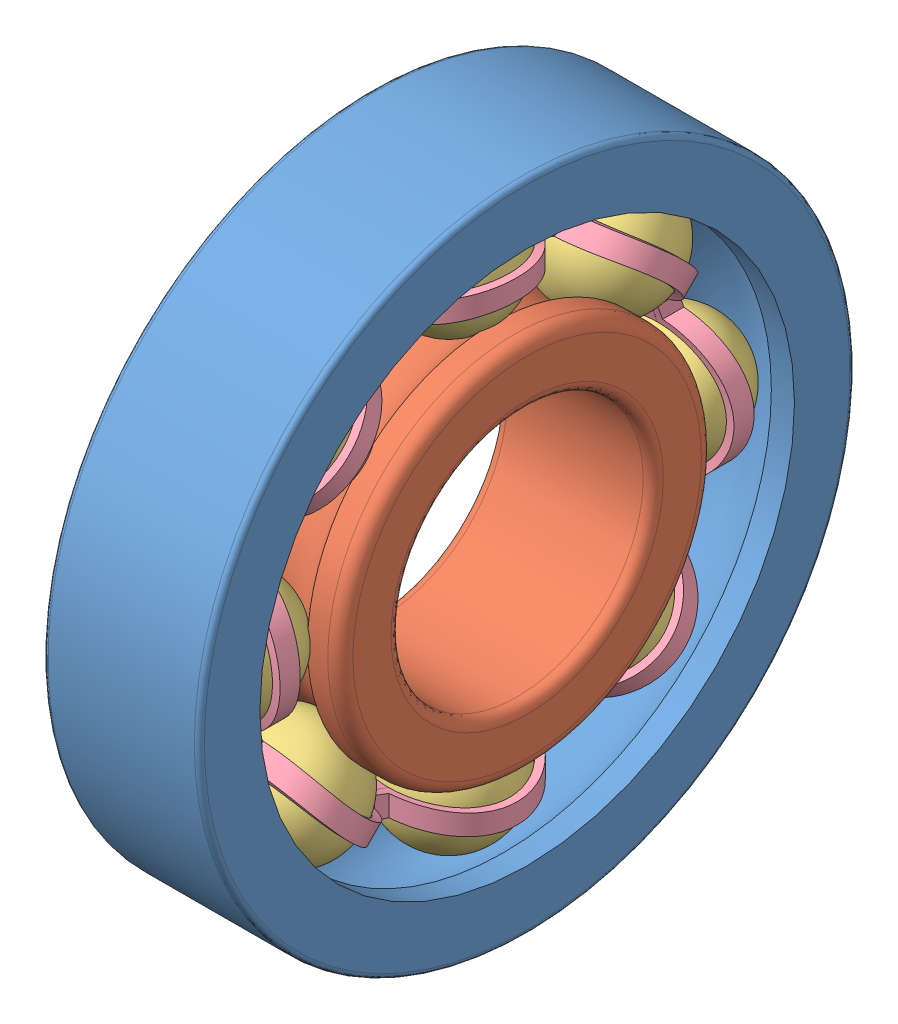
SolidWorks assembly Assem2, configuration Default. Lengths in mm.
Overall size (31 132.94 132.94).
22 component instances, 5 part files, 9 mates.
Components (placement in the parent):
- ball bearing 1-1: ball bearing 1 [Default] at origin size (31 132.94 132.94)
  - ball bearing-1: ball bearing [Default] at origin size (31 130 130)
    - Outer ring 1-1: Outer ring 1 [Default] at origin size (31 130 130)
    - Inner ring 1-1: Inner ring 1 [Default] at origin size (31 74.08 74.08)
    - ss ball-2: ss ball [Default] at (0 44.3297 0) size (24 24 24)
    - ss ball-3: ss ball [Default] at (0 31.3458 -31.3458) x (1 0 0) z (0 0.707107 0.707107) size (24 24 24)
    - ss ball-4: ss ball [Default] at (0 0 -44.3297) x (1 0 0) z (0 1 0) size (24 24 24)
    - ss ball-5: ss ball [Default] at (0 -31.3458 -31.3458) x (1 0 0) z (0 0.707107 -0.707107) size (24 24 24)
    - ss ball-6: ss ball [Default] at (0 -44.3297 0) x (1 0 0) z (0 0 -1) size (24 24 24)
    - ss ball-7: ss ball [Default] at (0 -31.3458 31.3458) x (1 0 0) z (0 -0.707107 -0.707107) size (24 24 24)
    - ss ball-8: ss ball [Default] at (0 0 44.3297) x (1 0 0) z (0 -1 0) size (24 24 24)
    - ss ball-9: ss ball [Default] at (0 31.3458 31.3458) x (1 0 0) z (0 -0.707107 0.707107) size (24 24 24)
  - cage-1: cage [Default] at (14 0 0) x (0 0 1) z (-1 0 0) size (94 94 14.93)
  - cage-2: cage [Default] at (-14 0 0) x (0 -0.707107 -0.707107) z (1 0 0) size (94 94 14.93)
- nut ball-1: nut ball [Default] at (0.1 -41.5746 17.2208) x (0 0 -1) z (1 0 0) size (2.3 2.3 1.4)
- nut ball-2: nut ball [Default] at (0.1 -17.2208 -41.5746) x (0 0 -1) z (1 0 0) size (2.3 2.3 1.4)
- nut ball-3: nut ball [Default] at (0.1 -41.5746 -17.2208) x (0 0 -1) z (1 0 0) size (2.3 2.3 1.4)
- nut ball-4: nut ball [Default] at (0.1 17.2208 -41.5746) x (0 0 -1) z (1 0 0) size (2.3 2.3 1.4)
- nut ball-5: nut ball [Default] at (0.1 41.5746 17.2208) x (0 0 -1) z (1 0 0) size (2.3 2.3 1.4)
- nut ball-6: nut ball [Default] at (2.9 17.2208 41.5746) x (0 -0.529706 0.848181) z (-1 0 0) size (2.3 2.3 1.4)
- nut ball-7: nut ball [Default] at (0.1 -17.2208 41.5746) x (0 0 -1) z (1 0 0) size (2.3 2.3 1.4)
- nut ball-8: nut ball [Default] at (0.1 41.5746 -17.2208) x (0 0 -1) z (1 0 0) size (2.3 2.3 1.4)
Mates (geometry in assembly coordinates):
- Coincident2: coincident anti-aligned: circle of ball bearing 1-1/cage-1; circle of nut ball-5
- Coincident3: coincident anti-aligned: circle of ball bearing 1-1/cage-1; circle of nut ball-8
- Coincident4: coincident anti-aligned: circle of ball bearing 1-1/cage-1; circle of nut ball-4
- Coincident5: coincident anti-aligned: circle of ball bearing 1-1/cage-1; circle of nut ball-2
- Coincident6: coincident anti-aligned: circle of ball bearing 1-1/cage-1; circle of nut ball-3
- Coincident7: coincident anti-aligned: circle of ball bearing 1-1/cage-1; circle of nut ball-1
- Coincident8: coincident anti-aligned: circle of ball bearing 1-1/cage-1; circle of nut ball-7
- Coincident9: coincident aligned: circle of ball bearing 1-1/cage-1; plane of nut ball-6 through (1.5 17.2208 41.5746) normal (-1 0 0)
- Coincident10: coincident aligned: circle of ball bearing 1-1/cage-1; circle of nut ball-6
